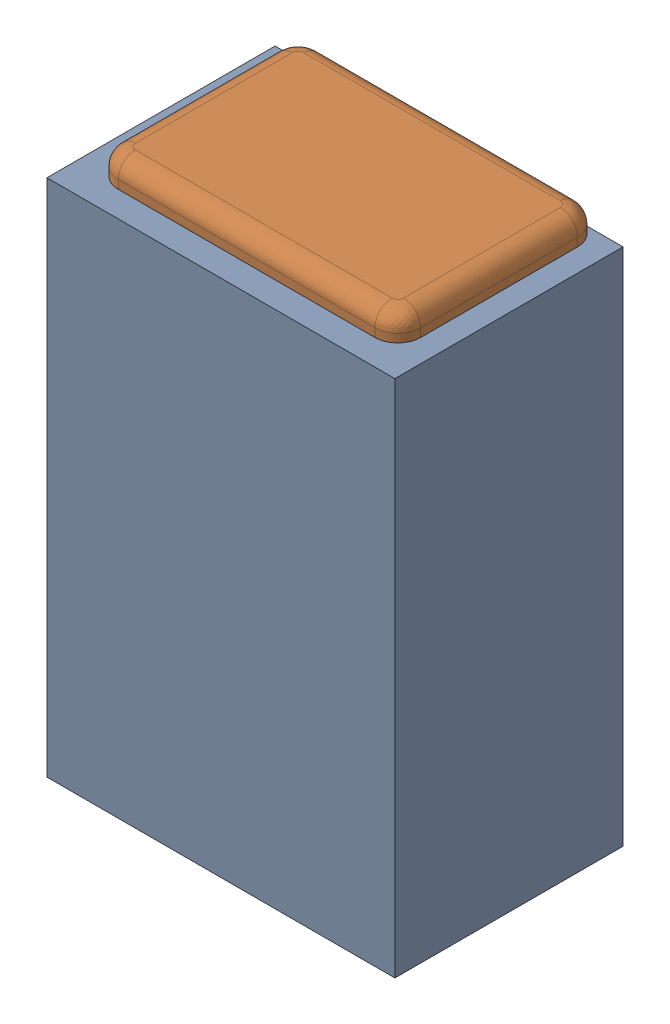
SolidWorks assembly C2, configuration Default. Lengths in mm.
Overall size (0.61 1 0.4).
3 component instances, 2 part files, 0 mates.
Components (placement in the parent):
- 1088881848-1: 1088881848 [Default] at (9.475 41.25 0) size (0.61 0.91 0.4)
  - Extruded-1-1: Extruded-1 [Default] at origin size (0.61 0.91 0.4)
- C0402-1: C0402 [Default] at (9.4751 41.2499 0) x (0 -1 0) z (-1 0 0) size (1 0.36 0.54)
